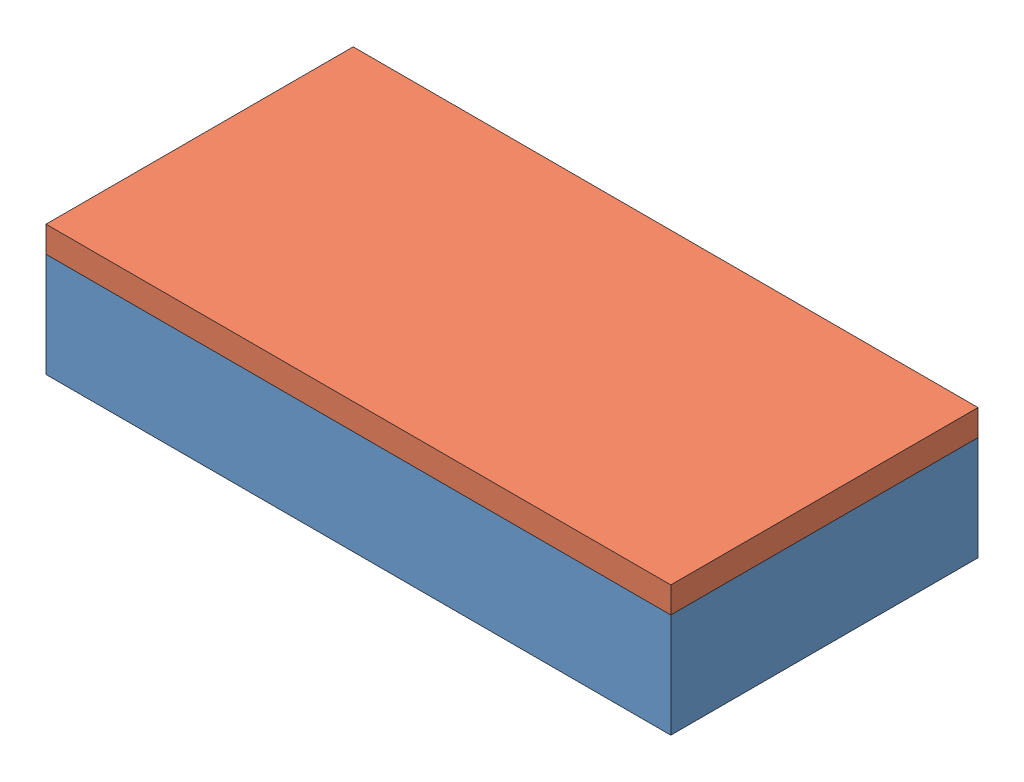
SolidWorks assembly Ensamblaje2, configuration Predeterminado. Lengths in mm.
Overall size (240 50 118).
2 component instances, 2 part files, 1 mates.
Components (placement in the parent):
- Barqueta 1-1: Barqueta 1 [Predeterminado] at (-60.9293 -9.7052 -0.6535) size (240 40.06 118)
- Barqueta 1.2 BASE MOLDE SUPERIOR-2: Barqueta 1.2 BASE MOLDE SUPERIOR [Predeterminado] at (-62.2442 -9.7052 0) size (240 34.66 118)
Mates (geometry in assembly coordinates):
- Coincidente2: coincident: point of assembly; point of assembly; moEndPointRef_w of Barqueta 1-1; moEndPointRef_w of Barqueta 1.2 BASE MOLDE SUPERIOR-2
